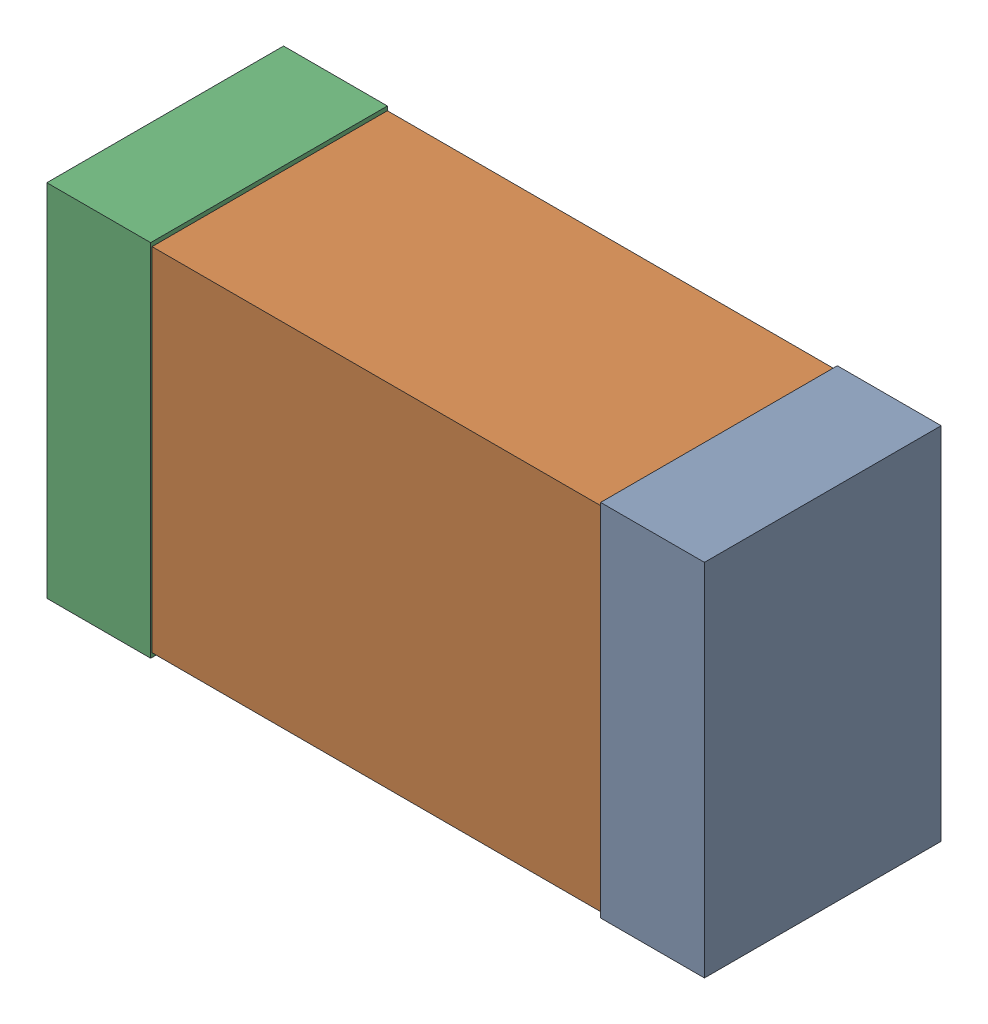
SolidWorks assembly CFFKanaloa_v2.0.0_Power, configuration Default. Lengths in mm.
Overall size (2.38 1.3 0.85).
6 component instances, 2 part files, 0 mates.
Components (placement in the parent):
- 352877648-1: 352877648 [Default] at (52.816 124.714 0) size (0.38 1.3 0.85)
  - Extruded_14-1: Extruded_14 [Default] at origin size (0.38 1.3 0.85)
- 352877904-1: 352877904 [Default] at (51.816 124.714 0) size (2.2 1.27 0.85)
  - Extruded_18-1: Extruded_18 [Default] at origin size (2.2 1.27 0.85)
- 352877648-2: 352877648 [Default] at (50.816 124.714 0) size (0.38 1.3 0.85)
  - Extruded_14-1: Extruded_14 [Default] at origin size (0.38 1.3 0.85)
